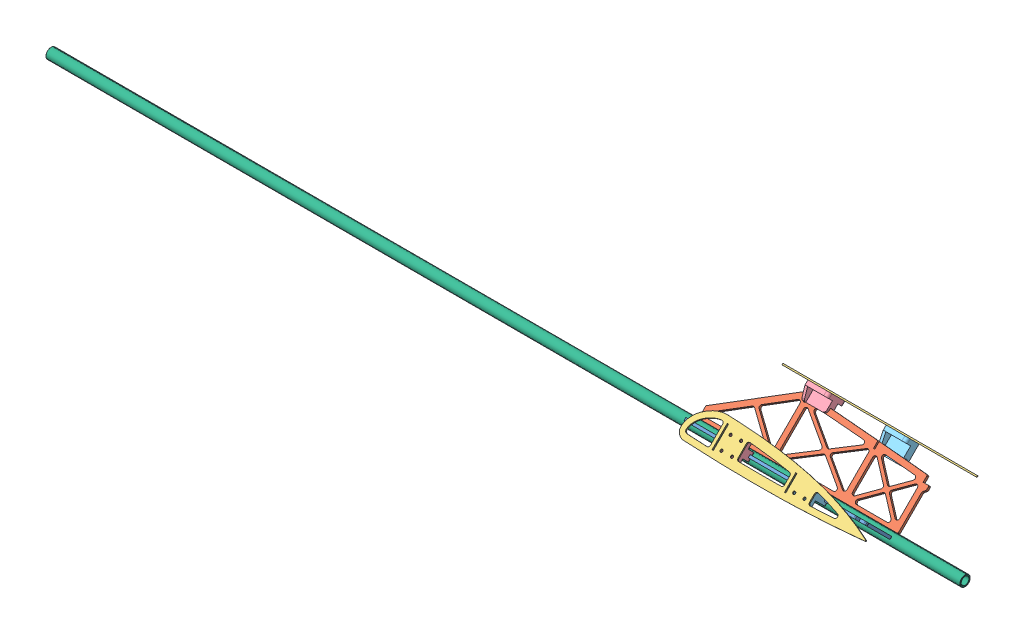
SolidWorks assembly Bracket, configuration Default. Lengths in mm.
Overall size (2235.2 162.28 290.01).
11 component instances, 7 part files, 32 mates.
Components (placement in the parent):
- Fuselage overlay-1: Fuselage overlay [Default] at (0 -50.8 0) x (1 0 0) z (0 1 0) size (2793.67 2931.42 567.28) (hidden)
- nacelle spar-1: nacelle spar [Default] at (0 -50.8 0) x (1 0 0) z (0 -0.707107 0.707107) size (493.71 132.93 6.4)
- Mirrornacelle spar-3: Mirrornacelle spar [Default] at (0 -50.8 0) x (1 0 0) z (0 0.707107 0.707107) size (493.71 132.93 6.4)
- nacelle break-1: nacelle break [Default] at (0 65.9433 116.7433) x (1 0 0) z (0 0.707107 0.707107) size (459.51 80.03 3.2)
- front nacelle mounting bracket (inner)-1: front nacelle mounting bracket (inner) [Default] at (1830.3875 65.9433 116.7433) x (1 0 0) z (0 -0.707107 0.707107) size (53.34 35.56 57.15)
- back nacelle mounting bracket (inner)-2: back nacelle mounting bracket (inner) [Default] at (2008.1875 65.9433 116.7433) x (1 0 0) z (0 -0.707107 0.707107) size (53.34 48.26 38.1)
- Mirrornacelle spar-2: Mirrornacelle spar [Default] at (0 -50.8 0) x (1 0 0) z (0 0.707107 0.707107) size (493.71 132.93 6.4) (suppressed, hidden)
- carbon main spar-1: carbon main spar [Default] at (76.2 -50.8 0) size (2235.2 25.4 25.4)
- nacelle break-3: nacelle break [Default] at (0 68.1884 -118.9884) x (1 0 0) z (0 -0.707107 0.707107) size (459.51 80.03 3.2)
- back nacelle mounting bracket (inner)-4: back nacelle mounting bracket (inner) [Default] at (2008.1875 52.4729 -130.2137) x (1 0 0) z (0 0.707107 0.707107) size (53.34 48.26 38.1)
- front nacelle mounting bracket (inner)-3: front nacelle mounting bracket (inner) [Default] at (1830.3875 65.9433 -116.7433) x (1 0 0) z (0 0.707107 0.707107) size (53.34 35.56 57.15)
Mates (geometry in assembly coordinates):
- Distance2: distance = 76.2 mm: plane of assembly through (0 0 0) normal (1 0 0); plane of assembly; plane of carbon main spar-1 through (76.2 -50.8 0) normal (1 0 0)
- Coincident3: coincident aligned: plane of carbon main spar-1 through (76.2 -50.8 0) normal (0 0 1)
- Distance21: distance = 50.8 mm aligned: plane of carbon main spar-1 through (76.2 -50.8 0) normal (0 1 0)
- Coincident8: coincident anti-aligned: plane of Fuesalage overlay-1 through (0 -50.8 0) normal (0 0 -1)
- Coincident9: coincident aligned: plane of Fuesalage overlay-1 through (0 -50.8 0) normal (1 0 0)
- Distance5: distance = 50.8 mm: plane of assembly through (0 0 0) normal (0 1 0); plane of Fuesalage overlay-1 through (0 -50.8 0) normal (0 1 0)
- Coincident47: coincident aligned: plane of Tail spar adapter-1 through (2306.6375 0 0) normal (0 0 1)
- Coincident48: coincident anti-aligned: plane of Tail spar adapter-1 through (2306.6375 0 0) normal (0 -1 0)
- Coincident53: coincident aligned: plane of Tail spar adapter-2 through (2315.5275 12.7 0) normal (0 0 1)
- Concentric1: concentric anti-aligned: cylinder of Tail spar adapter-1 through (2309.1775 33.3375 0) axis (-1 0 0) radius 2.5797; cylinder of Tail spar adapter-2 through (2312.9875 33.3375 0) axis (1 0 0) radius 2.5797
- Coincident54: coincident aligned: plane of carbon rear spar-1 through (2311.4 12.7 0) normal (0 0 1)
- Coincident55: coincident aligned: plane of carbon main spar-1 through (2311.4 -50.8 0) normal (1 0 0); plane of carbon rear spar-1 through (2311.4 12.7 0) normal (1 0 0)
- Concentric3: concentric anti-aligned: cylinder of Tail spar adapter-2 through (2312.9875 12.7 0) axis (1 0 0) radius 12.7; cylinder of carbon rear spar-1 through (2667 12.7 0) axis (-1 0 0) radius 12.7
- Coincident94: coincident anti-aligned: plane of nacelle spar-1 through (0 -50.8 0) normal (0 -0.707107 0.707107)
- Coincident95: coincident aligned: plane of nacelle spar-1 through (0 -50.8 0) normal (1 0 0)
- Coincident96: coincident: plane of nacelle spar-1 through (0 -50.8 0) normal (0 0.707107 0.707107)
- Coincident97: coincident aligned: plane of Mirrornacelle spar-3 through (0 -50.8 0) normal (1 0 0)
- Coincident98: coincident: plane of Mirrornacelle spar-3 through (0 -50.8 0) normal (0 0.707107 0.707107)
- Perpendicular1: perpendicular: plane of Mirrornacelle spar-3 through (0 -50.8 0) normal (0 0.707107 0.707107)
- Coincident100: coincident: plane of Mirrornacelle spar-3 through (0 -50.8 0) normal (0 0.707107 -0.707107)
- Coincident153: coincident aligned: plane of nacelle break-1 through (0 65.9433 116.7433) normal (1 0 0)
- Coincident156: coincident aligned: plane of nacelle break-1 through (0 97.5524 0) normal (0 0 1)
- Distance40: distance = 50.8 mm aligned: plane of nacelle break-1 through (0 -50.8 0) normal (0 1 0)
- Coincident157: coincident anti-aligned: plane of nacelle break-1 through (0 65.9433 116.7433) normal (0 -0.707107 -0.707107); plane of front nacelle mounting bracket (inner)-1 through (1830.3875 65.9433 116.7433) normal (0 0.707107 0.707107)
- Concentric8: concentric aligned: cylinder of nacelle break-1 through (1871.0275 -41.8379 -13.4885) axis (0 0.707107 0.707107) radius 3.175; cylinder of front nacelle mounting bracket (inner)-1 through (1871.0275 69.9844 98.3338) axis (0 0.707107 0.707107) radius 3.175
- Concentric9: concentric aligned: cylinder of nacelle break-1 through (1845.6275 -64.2885 8.9621) axis (0 0.707107 0.707107) radius 3.175; cylinder of front nacelle mounting bracket (inner)-1 through (1845.6275 47.5338 120.7844) axis (0 0.707107 0.707107) radius 3.175
- Coincident167: coincident anti-aligned: plane of nacelle break-1 through (0 65.9433 116.7433) normal (0 -0.707107 -0.707107); plane of back nacelle mounting bracket (inner)-2 through (2008.1875 65.9433 116.7433) normal (0 0.707107 0.707107)
- Concentric12: concentric aligned: cylinder of nacelle break-1 through (2023.4275 -64.2885 8.9621) axis (0 0.707107 0.707107) radius 3.175; cylinder of back nacelle mounting bracket (inner)-2 through (2023.4275 47.5338 120.7844) axis (0 0.707107 0.707107) radius 3.175
- Concentric13: concentric aligned: cylinder of nacelle break-1 through (2048.8275 -64.2885 8.9621) axis (0 0.707107 0.707107) radius 3.175; cylinder of back nacelle mounting bracket (inner)-2 through (2048.8275 47.5338 120.7844) axis (0 0.707107 0.707107) radius 3.175
- Distance45: distance = 50.8 mm aligned: plane of cockpit surface-1 through (0 -50.8 0) normal (0 1 0)
- Coincident222: coincident anti-aligned: plane of cockpit surface-1 through (0 -50.8 0) normal (0 0 -1)
- Coincident223: coincident aligned: plane of cockpit surface-1 through (0 -50.8 0) normal (1 0 0)
